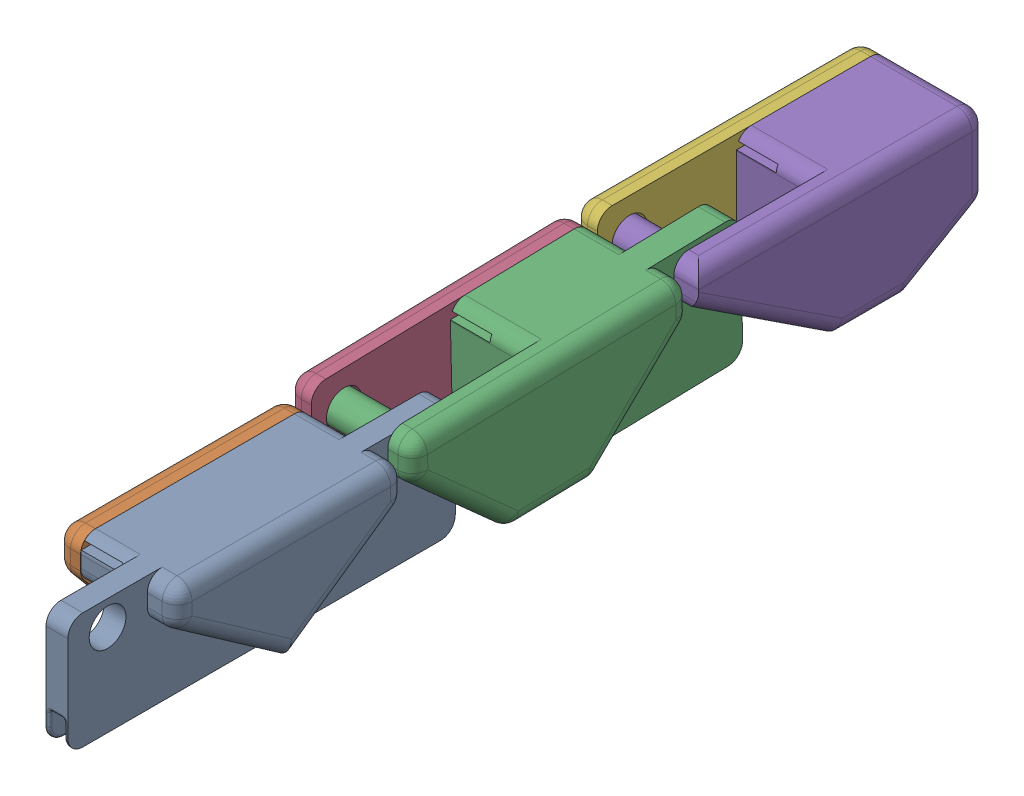
SolidWorks assembly pinky assembly, configuration Default. Lengths in mm.
Overall size (12.71 14.47 89.49).
6 component instances, 6 part files, 10 mates.
Components (placement in the parent):
- first_knuckle_michelle_R_5-1: first_knuckle_michelle_R_5 [Default] at (30.618 -1.6339 9.8564) size (11.1 11.7 39)
- first_knuckle_michelle_L_5-1: first_knuckle_michelle_L_5 [Default] at (-0.6602 -2.6339 12.768) x (0 0 -1) z (1 0 0) size (23.02 12.7 2.5)
- second_knuckle_michelle_R_5-1: second_knuckle_michelle_R_5 [Default] at (30.126 -1.2748 -23.6052) x (1 0 0) z (0 -0.023453 0.999725) size (11.6 12.7 36)
- second_knuckle_michelle_L_5-1: second_knuckle_michelle_L_5 [Default] at (-1.1522 -0.2522 -26.3423) x (0 0.023453 -0.999725) z (0 -0.999725 -0.023453) size (28 2.5 12.7)
- last_knuckle_michelleR_5-1: last_knuckle_michelleR_5 [Default] at (40.3024 -0.9596 -36.4991) size (11.6 12.7 29)
- last_knuckle_michelle_L_5-1: last_knuckle_michelle_L_5 [Default] at (-1.1442 -0.0015 -54.896) x (0 0 -1) z (0 -1 0) size (29 2.5 12.7)
Mates (geometry in assembly coordinates):
- Concentric1: concentric aligned: circle of first_knuckle_michelle_R_5-1; circle of first_knuckle_michelle_L_5-1
- Coincident1: coincident aligned: line of first_knuckle_michelle_R_5-1 through (1.8398 10.0661 -2.6878) axis (0 0 1); line of first_knuckle_michelle_L_5-1 through (1.8398 10.0661 -2.6878) axis (0 0 1)
- Concentric2: concentric aligned: circle of second_knuckle_michelle_R_5-1; circle of second_knuckle_michelle_L_5-1
- Coincident2: coincident aligned: line of second_knuckle_michelle_R_5-1 through (1.3478 11.6104 -31.3493) axis (0 -0.023453 0.999725); line of second_knuckle_michelle_L_5-1 through (1.3478 11.6104 -31.3493) axis (0 -0.023453 0.999725)
- Concentric3: concentric anti-aligned: circle of first_knuckle_michelle_R_5-1; circle of second_knuckle_michelle_R_5-1
- Distance1: distance = 0.508 mm: line of second_knuckle_michelle_R_5-1 through (9.0478 11.3524 -20.3523) axis (0 -0.023453 0.999725); line of first_knuckle_michelle_R_5-1 through (8.5398 10.0661 -2.6878) axis (0 0 -1)
- Concentric4: concentric anti-aligned: circle of last_knuckle_michelleR_5-1; circle of last_knuckle_michelle_L_5-1
- Coincident4: coincident aligned: line of last_knuckle_michelleR_5-1 through (1.3558 11.7404 -61.1799) axis (0 0 1); line of last_knuckle_michelle_L_5-1 through (1.3558 11.7404 -61.1799) axis (0 0 1)
- Concentric5: concentric anti-aligned: circle of second_knuckle_michelle_R_5-1; circle of last_knuckle_michelleR_5-1
- Distance2: distance = 0.508 mm: line of last_knuckle_michelleR_5-1 through (9.0558 11.7404 -49.1799) axis (0 0 1); line of second_knuckle_michelle_R_5-1 through (8.5478 11.6104 -31.3493) axis (0 0.023453 -0.999725)
